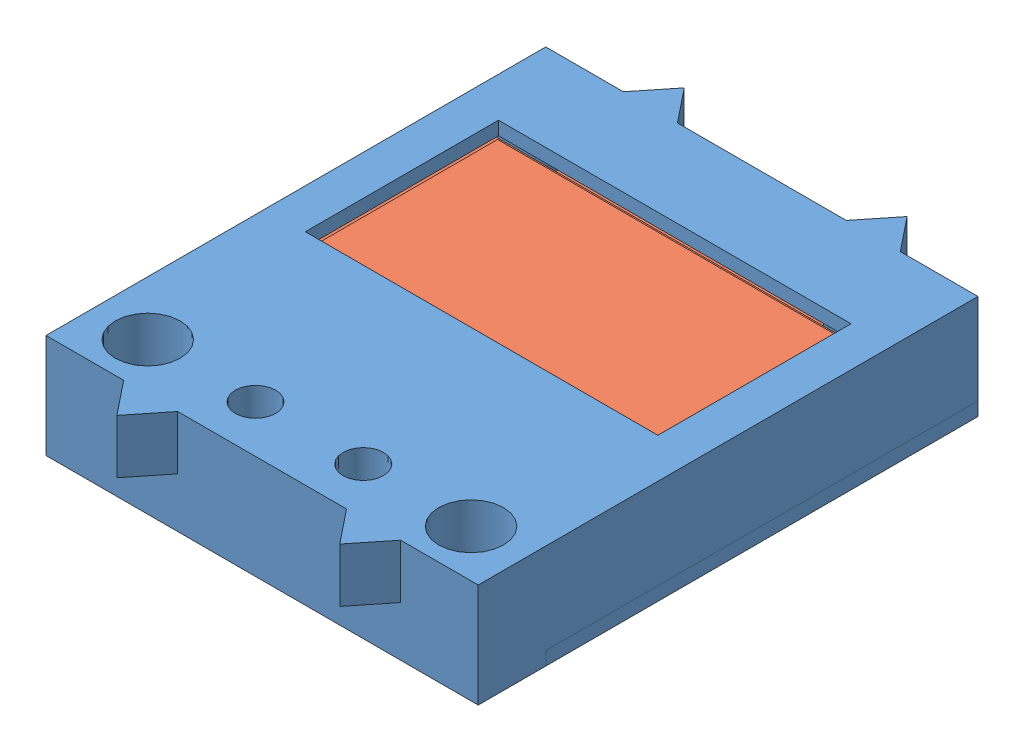
SolidWorks assembly Oloed case assy, configuration Default. Lengths in mm.
Overall size (32 22.6 42).
2 component instances, 2 part files, 2 mates.
Components (placement in the parent):
- OLED case-1: OLED case [Default] at (-111.0174 14.564 53.9689) size (32 22.6 42)
- OLED TFT 0.96 inch 64x128 monochrome-1: OLED TFT 0.96 inch 64x128 monochrome [Default] at (-95.0174 17.664 24.0689) size (27.3 12.3 27.8)
Mates (geometry in assembly coordinates):
- Coincident1: coincident anti-aligned: plane of OLED case-1 through (-111.0174 20.264 53.9689) normal (0 -1 0); plane of OLED TFT 0.96 inch 64x128 monochrome-1 through (-95.0174 20.264 24.0689) normal (0 1 0)
- Lock1: lock: unknown of OLED case-1; unknown of OLED TFT 0.96 inch 64x128 monochrome-1
